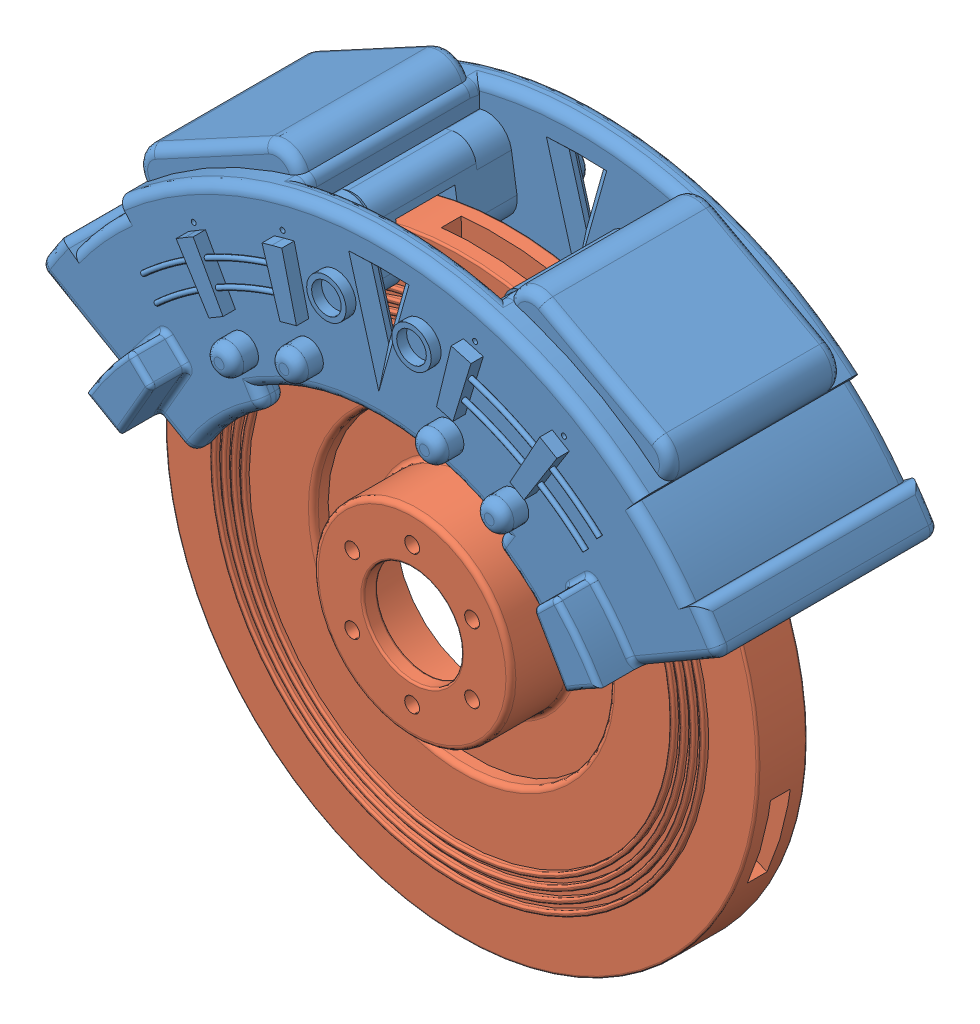
SolidWorks assembly Assem1, configuration Default. Lengths in mm.
Overall size (137.06 133.41 60.18).
2 component instances, 2 part files, 0 mates.
Components (placement in the parent):
- BRAKE CALIPER M99-1: BRAKE CALIPER M99 [Default] at origin size (137.06 57.76 60.18)
- disc of brake-1: disc of brake [Default] at (-1.3088 7.0608 -0.5457) size (120 120 20)
